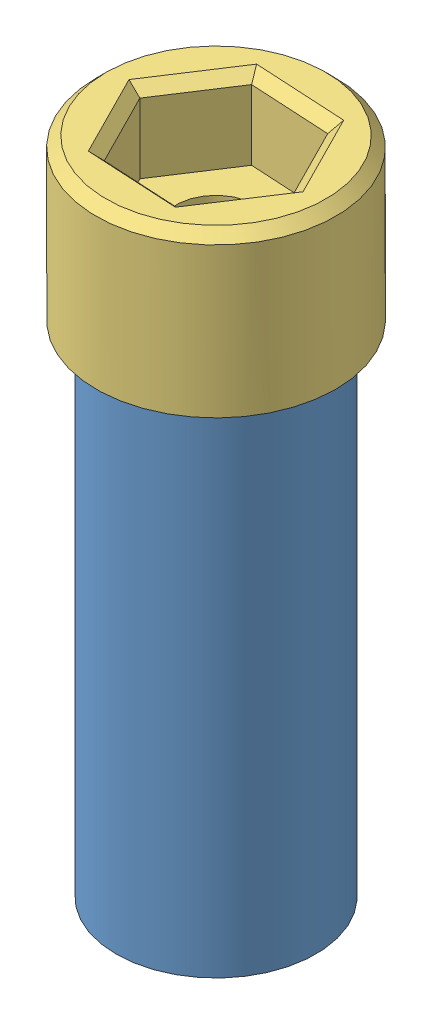
SolidWorks assembly Prirubnica_c.reg._sklop, configuration Default. Lengths in mm.
Overall size (33.22 66 33.22).
7 component instances, 3 part files, 8 mates.
Components (placement in the parent):
- prirubnica_cijevnog_registra-1: prirubnica_cijevnog_registra [Default] at (-7.5365 11.1278 62.3717) size (20 50 20)
- Gasket DIN 7603-AL-8-11_5-A(semering registra)-1: Gasket DIN 7603-AL-8-11_5-A(semering registra) [Default] at (-7.5365 26.6278 62.3717) x (0 -1 0) z (0.887885 0 0.460066) size (1 11.4 11.4)
- Gasket DIN 7603-AL-8-11_5-A(semering registra)-2: Gasket DIN 7603-AL-8-11_5-A(semering registra) [Default] at (-7.5365 28.6278 62.3717) x (0 -1 0) z (-0.546944 0 0.837169) size (1 11.4 11.4)
- Gasket DIN 7603-AL-8-11_5-A(semering registra)-3: Gasket DIN 7603-AL-8-11_5-A(semering registra) [Default] at (-7.5365 29.6278 62.3717) x (0 1 0) z (-0.564882 0 -0.825172) size (1 11.4 11.4)
- Gasket DIN 7603-AL-8-11_5-A(semering registra)-4: Gasket DIN 7603-AL-8-11_5-A(semering registra) [Default] at (-7.5365 30.6278 62.3717) x (0 1 0) z (-0.564882 0 -0.825172) size (1 11.4 11.4)
- Gasket DIN 7603-AL-8-11_5-A(semering registra)-5: Gasket DIN 7603-AL-8-11_5-A(semering registra) [Default] at (-7.5365 27.6278 62.3717) x (0 -1 0) z (-0.546944 0 0.837169) size (1 11.4 11.4)
- M16x30-1: M16x30 [Default] at (-7.5365 77.1278 62.3717) x (0 -1 0) z (-0.546944 0 0.837169) size (46 24 24)
Mates (geometry in assembly coordinates):
- Concentric1: concentric anti-aligned: circle of prirubnica_cijevnog_registra-1; circle of Gasket DIN 7603-AL-8-11_5-A(semering registra)-1
- Coincident1: coincident anti-aligned: plane of prirubnica_cijevnog_registra-1 through (-7.5365 26.1278 62.3717) normal (0 1 0); plane of Gasket DIN 7603-AL-8-11_5-A(semering registra)-1 through (-5.6503 26.1278 58.7314) normal (0 -1 0)
- Coincident3: coincident anti-aligned: circle of Gasket DIN 7603-AL-8-11_5-A(semering registra)-2; circle of Gasket DIN 7603-AL-8-11_5-A(semering registra)-3
- Coincident4: coincident aligned: circle of Gasket DIN 7603-AL-8-11_5-A(semering registra)-3; circle of Gasket DIN 7603-AL-8-11_5-A(semering registra)-4
- Coincident5: coincident aligned: circle of Gasket DIN 7603-AL-8-11_5-A(semering registra)-2; circle of Gasket DIN 7603-AL-8-11_5-A(semering registra)-5
- Coincident6: coincident aligned: circle of Gasket DIN 7603-AL-8-11_5-A(semering registra)-1; circle of Gasket DIN 7603-AL-8-11_5-A(semering registra)-5
- Concentric2: concentric aligned: cylinder of prirubnica_cijevnog_registra-1 through (-7.5365 26.1278 62.3717) axis (0 1 0) radius 7; cylinder of M16x30-1 through (-7.5365 165.8333 62.3717) axis (0 1 0) radius 7.981
- Coincident7: coincident anti-aligned: plane of Gasket DIN 7603-AL-8-11_5-A(semering registra)-4 through (-4.1533 31.1278 60.0557) normal (0 1 0); plane of M16x30-1 through (-7.5365 31.1278 62.3717) normal (0 -1 0)
